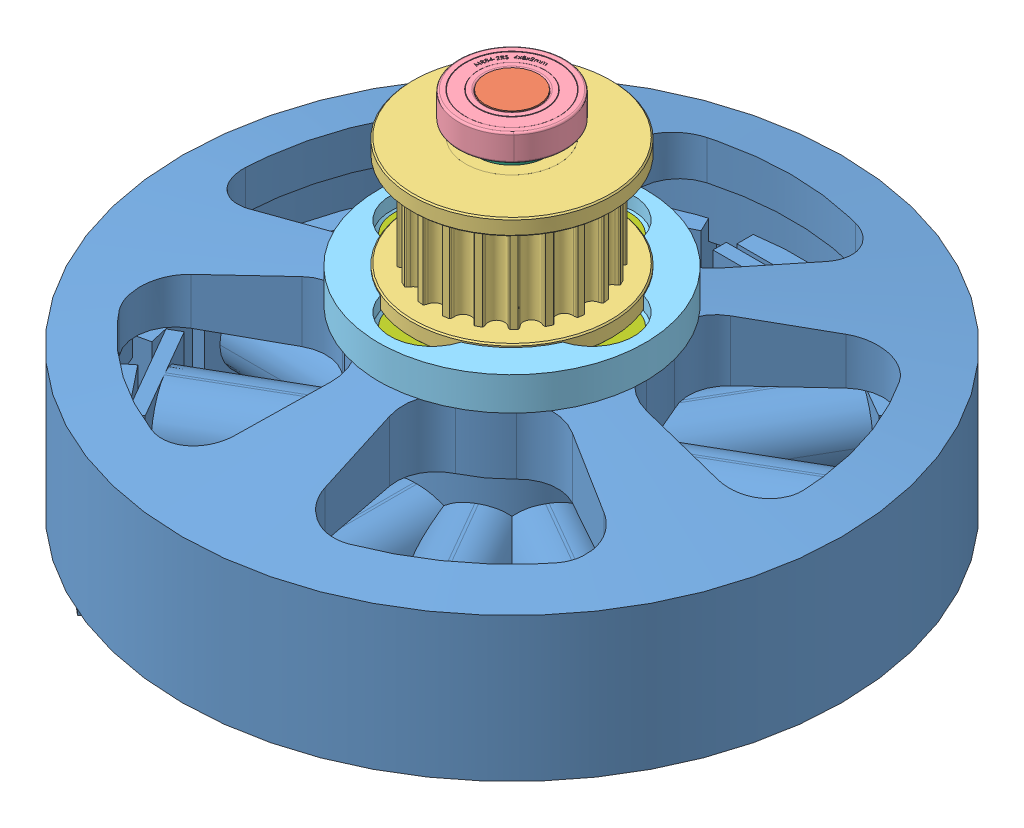
SolidWorks assembly Actuator_Module, configuration Default. Lengths in mm.
Overall size (49.6 36 49.6).
10 component instances, 7 part files, 14 mates.
Components (placement in the parent):
- BLDC_Motor_5010-1: BLDC_Motor_5010 [Varsayılan] at (23.9187 12.962 41.3722) size (49.6 20 49.6)
- MOTOR_SHAFT-1: MOTOR_SHAFT [Default] at (23.9187 28.962 41.3722) x (-0.884655 0 0.466247) z (-0.466247 0 -0.884655) size (4 36 4)
- Gates_2GT_20T_Toothed_Pulley-1: Gates_2GT_20T_Toothed_Pulley [Výchozí] at (23.9187 27.862 41.3722) x (0.949687 0 0.313202) z (-0.313202 0 0.949687) size (15 9.4 15)
- BEARING_MR84-2RS_4x8x2mm.step-4: BEARING_MR84-2RS_4x8x2mm.step [Default] at (23.9187 45.962 41.3722) x (-0.723388 0 -0.690442) z (0 -1 0) size (8 8 2)
- pulley-motor-interface-1: pulley-motor-interface [Default] at (23.9187 32.962 41.3722) size (20 2.5 20)
- bearing_spacer_1mm-1: bearing_spacer_1mm [Default] at (23.9187 43.862 41.3722) size (5.2 1 5.2)
- socket countersunk head screw_din-1: socket countersunk head screw_din [DIN 7991 - M3 x 8 --- 4.8N] at (29.9187 34.512 41.3722) x (0 -1 0) z (0.002985 0 0.999996) size (8 5.7 5.7)
- socket countersunk head screw_din-2: socket countersunk head screw_din [DIN 7991 - M3 x 8 --- 4.8N] at (23.9187 34.512 47.3722) x (0 -1 0) z (0.006654 0 0.999978) size (8 5.7 5.7)
- socket countersunk head screw_din-3: socket countersunk head screw_din [DIN 7991 - M3 x 8 --- 4.8N] at (17.9187 34.512 41.3722) x (0 -1 0) z (-0.019944 0 0.999801) size (8 5.7 5.7)
- socket countersunk head screw_din-4: socket countersunk head screw_din [DIN 7991 - M3 x 8 --- 4.8N] at (23.9187 34.512 35.3722) x (0 -1 0) z (-0.046377 0 0.998924) size (8 5.7 5.7)
Mates (geometry in assembly coordinates):
- Concentric2: concentric anti-aligned: cylinder of BLDC_Motor_5010-1 through (23.9187 12.962 41.3722) axis (0 1 0) radius 2; cylinder of MOTOR_SHAFT-1 through (23.9187 46.962 41.3722) axis (0 -1 0) radius 2
- Distance1: distance = 2 mm aligned: plane of BLDC_Motor_5010-1 through (23.9187 12.962 41.3722) normal (0 -1 0); plane of MOTOR_SHAFT-1 through (23.9187 10.962 41.3722) normal (0 -1 0)
- Concentric3: concentric aligned: cylinder of MOTOR_SHAFT-1 through (23.9187 46.962 41.3722) axis (0 -1 0) radius 2; cylinder of Gates_2GT_20T_Toothed_Pulley-1 through (23.9187 42.662 41.3722) axis (0 -1 0) radius 2
- Concentric4: concentric aligned: cylinder of MOTOR_SHAFT-1 through (23.9187 46.962 41.3722) axis (0 -1 0) radius 2; cylinder of BEARING_MR84-2RS_4x8x2mm.step-4 through (23.9187 28.462 41.3722) axis (0 -1 0) radius 2
- Coincident3: coincident aligned: plane of MOTOR_SHAFT-1 through (23.9187 46.962 41.3722) normal (0 1 0); plane of BEARING_MR84-2RS_4x8x2mm.step-4 through (25.6448 46.962 39.5637) normal (0 1 0)
- Concentric5: concentric aligned: cylinder of Gates_2GT_20T_Toothed_Pulley-1 through (23.9187 56.8752 41.3722) axis (0 -1 0) radius 7.5; cylinder of pulley-motor-interface-1 through (23.9187 35.462 41.3722) axis (0 -1 0) radius 7.5
- Concentric6: concentric anti-aligned: cylinder of BLDC_Motor_5010-1 through (29.9187 29.462 41.3722) axis (0 1 0) radius 1.5; cylinder of pulley-motor-interface-1 through (29.9187 55.462 41.3722) axis (0 -1 0) radius 3.15
- Coincident4: coincident anti-aligned: plane of BLDC_Motor_5010-1 through (25.4187 32.962 41.3722) normal (0 1 0); plane of pulley-motor-interface-1 through (23.9187 32.962 41.3722) normal (0 -1 0)
- Coincident5: coincident anti-aligned: plane of Gates_2GT_20T_Toothed_Pulley-1 through (18.5868 34.462 38.928) normal (0 -1 0); plane of pulley-motor-interface-1 through (23.9187 34.462 41.3722) normal (0 1 0)
- Concentric8: concentric aligned: cylinder of MOTOR_SHAFT-1 through (23.9187 46.962 41.3722) axis (0 -1 0) radius 2; cylinder of bearing_spacer_1mm-1 through (23.9187 44.862 41.3722) axis (0 -1 0) radius 2
- Coincident6: coincident aligned: cone of pulley-motor-interface-1 through (29.9187 34.462 41.3722) axis (0 -1 0); cone of socket countersunk head screw_din-1 through (29.9187 34.162 41.3722) axis (0 -1 0)
- Coincident7: coincident aligned: cone of pulley-motor-interface-1 through (23.9187 34.462 47.3722) axis (0 -1 0); cone of socket countersunk head screw_din-2 through (23.9187 34.162 47.3722) axis (0 -1 0)
- Coincident8: coincident aligned: cone of pulley-motor-interface-1 through (17.9187 34.462 41.3722) axis (0 -1 0); cone of socket countersunk head screw_din-3 through (17.9187 34.162 41.3722) axis (0 -1 0)
- Coincident9: coincident aligned: cone of pulley-motor-interface-1 through (23.9187 34.462 35.3722) axis (0 -1 0); cone of socket countersunk head screw_din-4 through (23.9187 34.162 35.3722) axis (0 -1 0)
